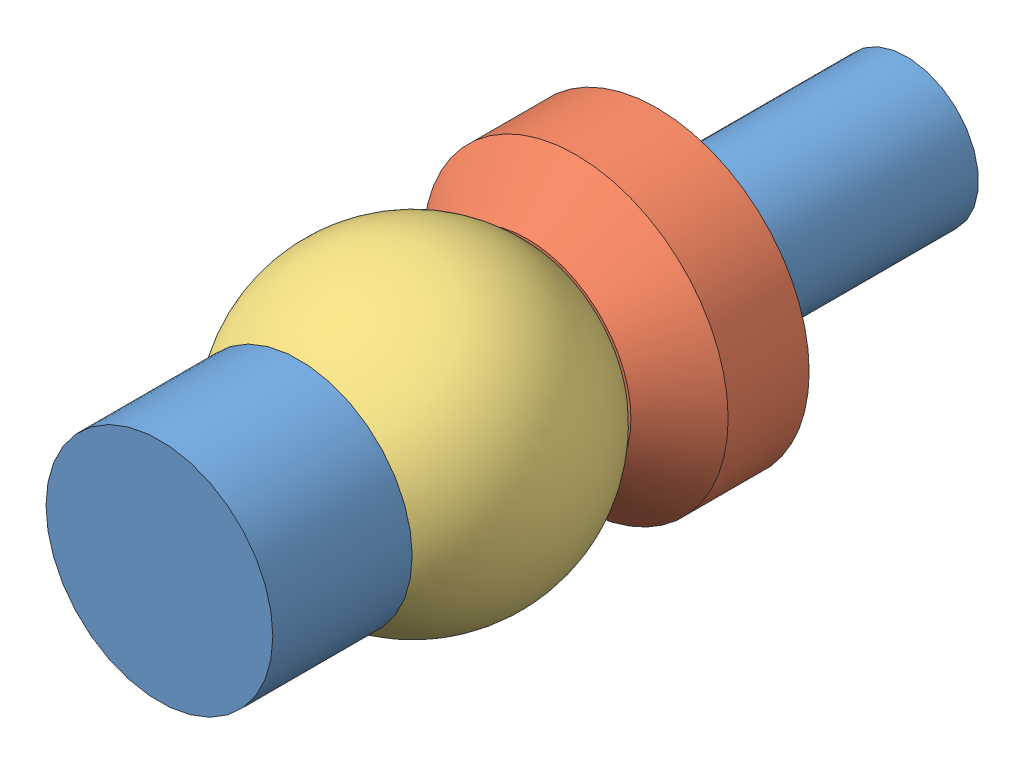
SolidWorks assembly Assem1, configuration Default. Lengths in mm.
Overall size (4.78 4.78 11.71).
3 component instances, 3 part files, 6 mates.
Components (placement in the parent):
- 2-56_0.375_Socket_Head_Cap_Screw_MC-92196A079-1: 2-56_0.375_Socket_Head_Cap_Screw_MC-92196A079 [Default] at (0 0 -0.0902) size (3.56 3.56 11.71)
- 2-56_Ball_Joint_Base-1: 2-56_Ball_Joint_Base [Default] at (0 0 3.8214) size (4.78 4.78 2.03)
- 2-56_Ball_Joint_Half_Sphere-1: 2-56_Ball_Joint_Half_Sphere [Default] at (0 0 7.6441) x (1 0 0) z (0 -1 0) size (4.78 3.58 4.78)
Mates (geometry in assembly coordinates):
- Coincident1: coincident aligned: plane of 2-56_0.375_Socket_Head_Cap_Screw_MC-92196A079-1 through (0 0 -0.0902) normal (1 0 0); plane of assembly
- Coincident2: coincident aligned: plane of 2-56_0.375_Socket_Head_Cap_Screw_MC-92196A079-1 through (0 0 -0.0902) normal (0 1 0); plane of assembly
- Concentric1: concentric anti-aligned: cylinder of 2-56_0.375_Socket_Head_Cap_Screw_MC-92196A079-1 through (0 0 9.4348) axis (0 0 -1) radius 1.1303; cylinder of 2-56_Ball_Joint_Half_Sphere-1 through (0 0 5.8534) axis (0 0 1) radius 1.1303
- Coincident3: coincident anti-aligned: plane of 2-56_0.375_Socket_Head_Cap_Screw_MC-92196A079-1 through (0 0 9.4348) normal (0 0 -1); plane of 2-56_Ball_Joint_Half_Sphere-1 through (0 0 9.4348) normal (0 0 1)
- Concentric2: concentric aligned: cylinder of 2-56_0.375_Socket_Head_Cap_Screw_MC-92196A079-1 through (0 0 9.4348) axis (0 0 -1) radius 1.1303; cylinder of 2-56_Ball_Joint_Base-1 through (0 0 5.8534) axis (0 0 -1) radius 1.1303
- Coincident4: coincident anti-aligned: plane of 2-56_Ball_Joint_Base-1 through (0 0 5.8534) normal (0 0 1); plane of 2-56_Ball_Joint_Half_Sphere-1 through (0 0 5.8534) normal (0 0 -1)
